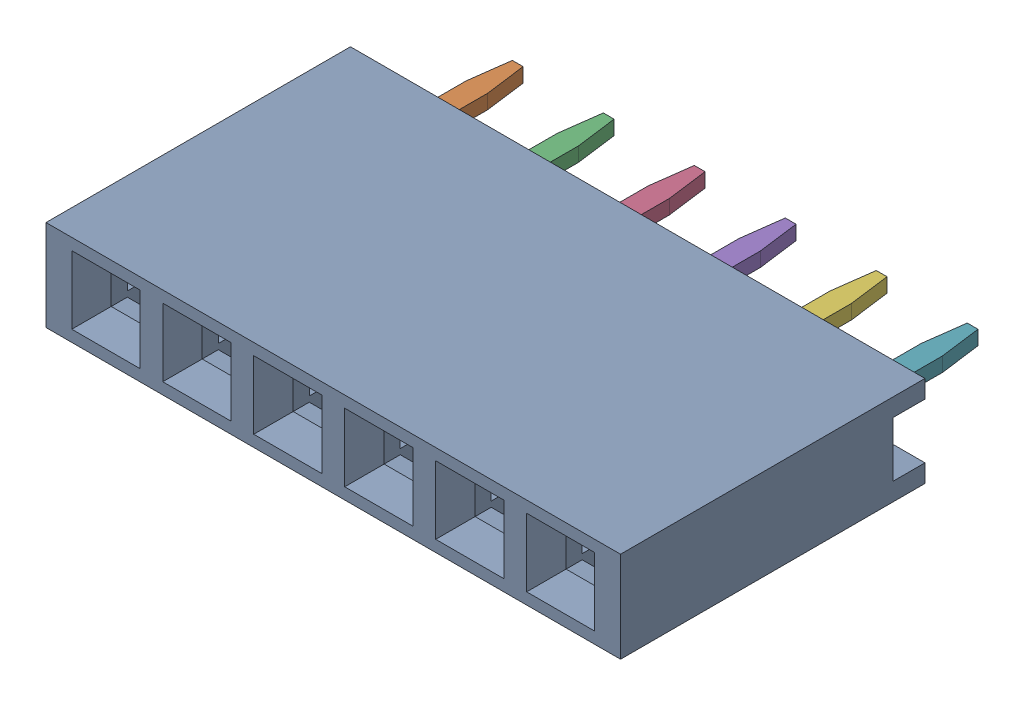
SolidWorks assembly DS1023-1x6SF11_1.step, configuration Default. Lengths in mm.
Overall size (16.04 2.54 11.5).
7 component instances, 2 part files, 0 mates.
Components (placement in the parent):
- body_3.step-8: body_3.step [Default] at origin size (16.04 2.54 8.5)
- contact_1.step-51: contact_1.step [Default] at origin size (2.3 0.4 9)
- contact_1.step-52: contact_1.step [Default] at (2.54 0 0) size (2.3 0.4 9)
- contact_1.step-55: contact_1.step [Default] at (5.08 0 0) size (2.3 0.4 9)
- contact_1.step-56: contact_1.step [Default] at (7.62 0 0) size (2.3 0.4 9)
- contact_1.step-57: contact_1.step [Default] at (10.16 0 0) size (2.3 0.4 9)
- contact_1.step-58: contact_1.step [Default] at (12.7 0 0) size (2.3 0.4 9)
